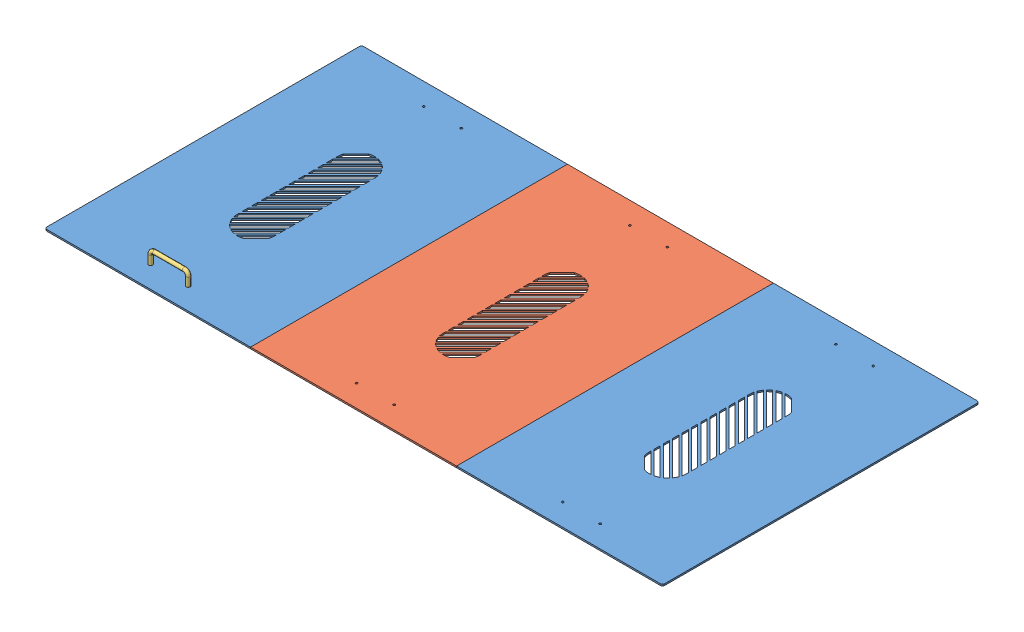
SolidWorks assembly cover_assembly, configuration Default. Lengths in mm.
Overall size (1255.7 32.54 643.89).
4 component instances, 3 part files, 9 mates.
Components (placement in the parent):
- germ_cover02-1: germ_cover02 [Default] at (-22.2289 7.8475 5.3199) size (418.57 3.17 643.89)
- germ_cover01-1: germ_cover01 [Default] at (396.3377 7.8475 5.3199) size (418.57 3.17 643.89)
- germ_cover02-2: germ_cover02 [Default] at (814.9043 11.0225 5.3199) x (-1 0 0) z (0 0 1) size (418.57 3.17 643.89)
- germ_handle-1: germ_handle [Default] at (-60.3924 11.0225 282.8149) size (84.14 29.37 7.94)
Mates (geometry in assembly coordinates):
- Coincident1: coincident aligned: plane of germ_cover02-1 through (-22.2289 11.0225 5.3199) normal (0 1 0); plane of germ_cover01-1 through (396.3377 11.0225 5.3199) normal (0 1 0)
- Coincident2: coincident anti-aligned: plane of germ_cover02-1 through (187.0544 11.0225 327.2649) normal (1 0 0); plane of germ_cover01-1 through (187.0544 11.0225 327.2649) normal (-1 0 0)
- Coincident3: coincident aligned: plane of germ_cover02-1 through (-231.5122 11.0225 327.2649) normal (0 0 1); plane of germ_cover01-1 through (187.0544 11.0225 327.2649) normal (0 0 1)
- Coincident4: coincident aligned: plane of germ_cover01-1 through (396.3377 11.0225 5.3199) normal (0 1 0); plane of germ_cover02-2 through (814.9043 11.0225 5.3199) normal (0 1 0)
- Coincident5: coincident anti-aligned: plane of germ_cover01-1 through (605.621 11.0225 327.2649) normal (1 0 0); plane of germ_cover02-2 through (605.621 7.8475 327.2649) normal (-1 0 0)
- Coincident6: coincident aligned: plane of germ_cover01-1 through (187.0544 11.0225 327.2649) normal (0 0 1); plane of germ_cover02-2 through (1024.1876 7.8475 327.2649) normal (0 0 1)
- Concentric1: concentric aligned: circle of germ_cover02-1; circle of germ_handle-1
- Concentric2: concentric anti-aligned: circle of germ_cover02-1; circle of germ_handle-1
- Coincident7: coincident anti-aligned: plane of germ_cover02-1 through (-22.2289 11.0225 5.3199) normal (0 1 0); plane of germ_handle-1 through (-60.3924 11.0225 282.8149) normal (0 -1 0)
